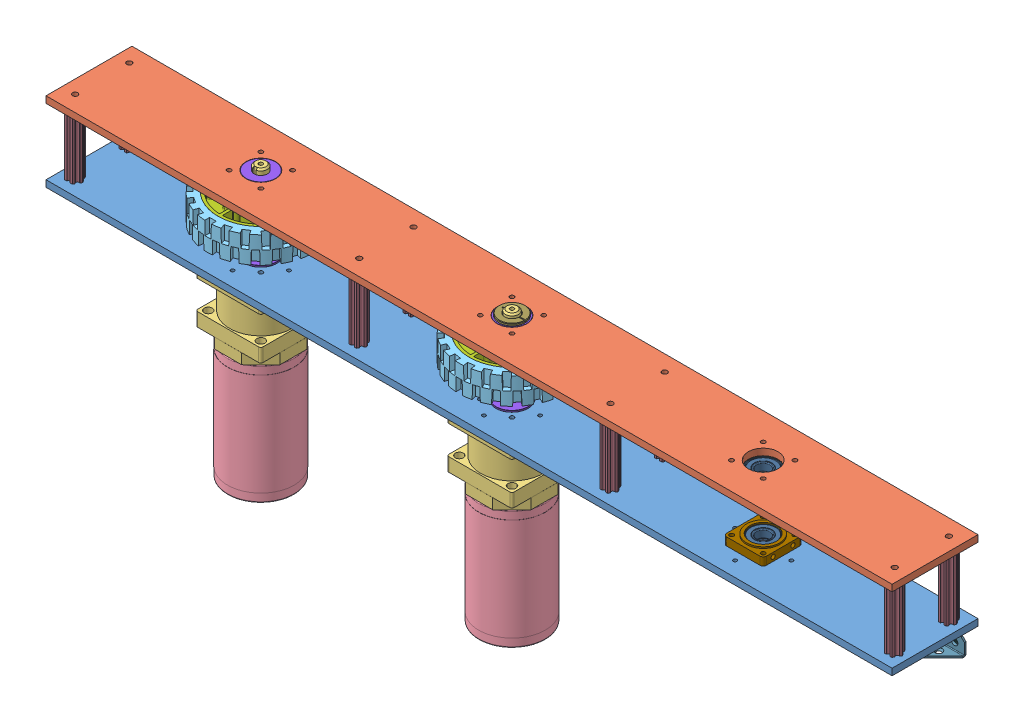
SolidWorks assembly Drive Side 32- version current 1-20-17, configuration Default. Lengths in mm.
Overall size (812.8 264.42 150.72).
38 component instances, 15 part files, 0 mates.
Components (placement in the parent):
- Part 1_1-1: Part 1_1 [Default] at (-41.6353 24.5131 42.8723) size (812.8 6.35 82.55)
- Part 1_1_2-1: Part 1_1_2 [Default] at (-41.6353 94.3631 42.8723) size (812.8 6.35 82.55)
- Part 5_1-1: Part 5_1 [Default] at (-293.1186 5.1631 48.3276) x (0 0 -1) z (1 0 0) size (62.86 145.05 62.86)
- Part 5_1-2: Part 5_1 [Default] at (-47.0906 5.1631 32.689) size (62.86 145.05 62.86)
- am-0255 2.5inch CIM Motor_1-1: am-0255 2.5inch CIM Motor_1 [Default] at (-318.4953 -64.3869 152.1685) x (1 0 0) z (0 1 0) size (64.01 64.01 154.94)
- am-0255 2.5inch CIM Motor_1-2: am-0255 2.5inch CIM Motor_1 [Default] at (-77.1953 -64.3869 152.1685) x (1 0 0) z (0 1 0) size (64.01 64.01 154.94)
- 4 in tread_1-1: 4 in tread_1 [Default] at (-282.9353 63.8121 42.8723) x (0 1 0) z (0 0 1) size (25.4 101.6 101.6)
- 4in 2013 Hub_1-1: 4in 2013 Hub_1 [Default] at (-282.9353 63.8121 42.8723) x (0 1 0) z (1 0 0) size (17.56 82.55 82.55)
- 4in 2013 Hub_1_2-1: 4in 2013 Hub_1_2 [Default] at (-282.9353 63.8121 42.8723) x (0 1 0) z (1 0 0) size (17.56 82.55 82.55)
- 4 in tread_1-2: 4 in tread_1 [Default] at (-41.6353 67.1549 42.8723) x (0 -1 0) z (0 0 1) size (25.4 101.6 101.6)
- 4in 2013 Hub_1-2: 4in 2013 Hub_1 [Default] at (-41.6353 67.1549 42.8723) x (0 1 0) z (1 0 0) size (17.56 82.55 82.55)
- 4in 2013 Hub_1_2-2: 4in 2013 Hub_1_2 [Default] at (-41.6353 67.1549 42.8723) x (0 1 0) z (1 0 0) size (17.56 82.55 82.55)
- am-0030 0.5''''id Flanged, Shielded Ball Bearing (FR8ZZ)_1-1: am-0030 0.5''''id Flanged, Shielded Ball Bearing (FR8ZZ)_1 [Default] at (-41.6353 94.4165 42.8723) x (1 0 0) z (0 -1 0) size (31.12 31.12 7.93)
- am-0030 0.5''''id Flanged, Shielded Ball Bearing (FR8ZZ)_1-2: am-0030 0.5''''id Flanged, Shielded Ball Bearing (FR8ZZ)_1 [Default] at (-41.6353 18.1098 42.8723) x (1 0 0) z (0 1 0) size (31.12 31.12 7.93)
- am-0030 0.5''''id Flanged, Shielded Ball Bearing (FR8ZZ)_1-3: am-0030 0.5''''id Flanged, Shielded Ball Bearing (FR8ZZ)_1 [Default] at (-282.9353 94.4165 42.8723) x (1 0 0) z (0 -1 0) size (31.12 31.12 7.93)
- P60 bearing block_1-1: P60 bearing block_1 [Default] at (184.6301 84.0337 22.2734) x (0 1 0) z (1 0 0) size (9.02 38.25 38.25)
- R8ZZ Bearing_1-1: R8ZZ Bearing_1 [Default] at (220.2635 84.3512 27.8377) x (0 1 0) z (0 0 1) size (7.94 28.58 28.58)
- P60 bearing block_1-2: P60 bearing block_1 [Default] at (184.6301 28.4926 63.4711) x (0 -1 0) z (1 0 0) size (9.02 38.25 38.25)
- R8ZZ Bearing_1-2: R8ZZ Bearing_1 [Default] at (220.2635 139.9137 27.8377) x (0 1 0) z (0 0 1) size (7.94 28.58 28.58)
- 500 Key Hub r2_1-1: 500 Key Hub r2_1 [Default] at (-282.9353 80.3856 42.8723) x (-1 0 0) z (0 1 0) size (57.15 57.15 25.4)
- 500 Key Hub r2_1-2: 500 Key Hub r2_1 [Default] at (-41.6353 50.5814 42.8723) x (1 0 0) z (0 -1 0) size (57.15 57.15 25.4)
- 500 Key Hub r2_1-3: 500 Key Hub r2_1 [Default] at (-282.9353 47.2386 42.8723) x (1 0 0) z (0 -1 0) size (57.15 57.15 25.4)
- 500 Key Hub r2_1-4: 500 Key Hub r2_1 [Default] at (-41.6353 83.7284 42.8723) x (-1 0 0) z (0 1 0) size (57.15 57.15 25.4)
- am-0030 0.5''''id Flanged, Shielded Ball Bearing (FR8ZZ)_1-4: am-0030 0.5''''id Flanged, Shielded Ball Bearing (FR8ZZ)_1 [Default] at (-282.9353 18.1098 42.8723) x (1 0 0) z (0 1 0) size (31.12 31.12 7.93)
- 217-2736.20121205_1-1: 217-2736.20121205_1 [Default] at (-37.0221 40.4543 45.4879) x (1 0 0) z (0 1 0) size (25.39 25.4 6.35)
- 217-2736.20121205_1-2: 217-2736.20121205_1 [Default] at (-37.0221 93.8554 40.2567) x (1 0 0) z (0 -1 0) size (25.39 25.4 6.35)
- 217-2736.20121205_1-3: 217-2736.20121205_1 [Default] at (-278.3221 37.1115 45.4879) x (1 0 0) z (0 1 0) size (25.39 25.4 6.35)
- 217-2736.20121205_1-4: 217-2736.20121205_1 [Default] at (-278.3221 90.5127 40.2567) x (1 0 0) z (0 -1 0) size (25.39 25.4 6.35)
- am-churro 500 churro tube_1-1: am-churro 500 churro tube_1 [Default] at (-435.3353 24.5131 68.9073) x (1 0 0) z (0 1 0) size (14.66 12.7 63.5)
- am-churro 500 churro tube_1-2: am-churro 500 churro tube_1 [Default] at (-435.3353 24.5131 16.8373) x (1 0 0) z (0 1 0) size (14.66 12.7 63.5)
- am-churro 500 churro tube_1-3: am-churro 500 churro tube_1 [Default] at (352.0647 24.5131 68.9073) x (1 0 0) z (0 1 0) size (14.66 12.7 63.5)
- am-churro 500 churro tube_1-4: am-churro 500 churro tube_1 [Default] at (352.0647 24.5131 16.8373) x (1 0 0) z (0 1 0) size (14.66 12.7 63.5)
- am-churro 500 churro tube_1-5: am-churro 500 churro tube_1 [Default] at (-162.2853 24.5131 16.8373) x (1 0 0) z (0 1 0) size (14.66 12.7 63.5)
- am-churro 500 churro tube_1-6: am-churro 500 churro tube_1 [Default] at (79.0147 24.5131 68.9073) x (1 0 0) z (0 1 0) size (14.66 12.7 63.5)
- am-churro 500 churro tube_1-7: am-churro 500 churro tube_1 [Default] at (79.0147 24.5131 16.8373) x (1 0 0) z (0 1 0) size (14.66 12.7 63.5)
- am-churro 500 churro tube_1-8: am-churro 500 churro tube_1 [Default] at (-162.2853 24.5131 68.9073) x (1 0 0) z (0 1 0) size (14.66 12.7 63.5)
- 1088A310_INSIDE CORNER-REINFORCING BRACKET-1: 1088A310_INSIDE CORNER-REINFORCING BRACKET [1088A31] at (283.0196 -30.976 -17.8126) size (50.93 15.88 50.93)
- 90975A029_ZNC-PLTD STL TEE NUT INSERTS-1: 90975A029_ZNC-PLTD STL TEE NUT INSERTS [90975A029] at (288.0222 -58.1269 -47.5264) size (19.05 15.92 19.05)
